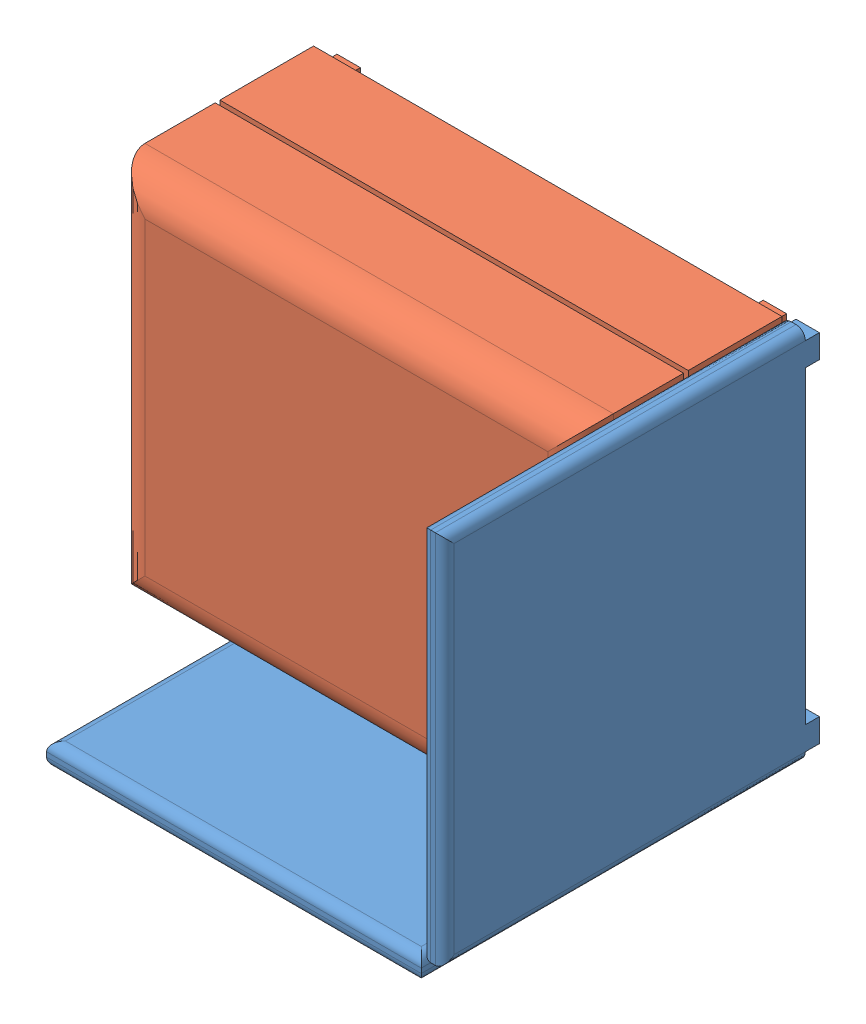
SolidWorks assembly Sofa-L, configuration Standard. Lengths in mm.
Overall size (1050 850 800).
3 component instances, 2 part files, 6 mates.
Components (placement in the parent):
- Rückenstütze-80x80-1: Rückenstütze-80x80 [Standard] at (48.0974 -746.2493 765.6126) size (800 50 800)
- Sitzelement-1: Sitzelement [Standard] at (-51.9026 -321.2493 795.6126) x (0 -1 0) z (-1 0 0) size (800 460 1000)
- Rückenstütze-80x80-3: Rückenstütze-80x80 [Standard] at (473.0974 -321.2493 765.6126) x (0 -1 0) z (0 0 1) size (800 50 800)
Mates (geometry in assembly coordinates):
- Deckungsgleich2: coincident aligned: plane of Rückenstütze-80x80-1 through (48.0974 -746.2493 765.6126) normal (0 0 -1); plane of Sitzelement-1 through (-51.9026 -321.2493 765.6126) normal (0 0 -1)
- Deckungsgleich3: coincident aligned: plane of Rückenstütze-80x80-1 through (448.0974 -771.2493 1565.6126) normal (1 0 0); plane of Sitzelement-1 through (448.0974 78.7507 995.6126) normal (1 0 0)
- Deckungsgleich13: coincident anti-aligned: plane of Rückenstütze-80x80-1 through (-331.9026 -721.2493 795.6126) normal (0 1 0); plane of Sitzelement-1 through (-551.9026 -721.2493 995.6126) normal (0 -1 0)
- Deckungsgleich14: coincident: plane of Sitzelement-1 through (-51.9026 -321.2493 765.6126) normal (0 0 -1); plane of Rückenstütze-80x80-3 through (473.0974 -321.2493 765.6126) normal (0 0 -1)
- Deckungsgleich15: coincident: plane of Sitzelement-1 through (448.0974 78.7507 995.6126) normal (1 0 0); plane of Rückenstütze-80x80-3 through (448.0974 58.7507 795.6126) normal (-1 0 0)
- Deckungsgleich16: coincident aligned: plane of Sitzelement-1 through (-551.9026 -721.2493 995.6126) normal (0 -1 0); plane of Rückenstütze-80x80-3 through (448.0974 -721.2493 1565.6126) normal (0 -1 0)
